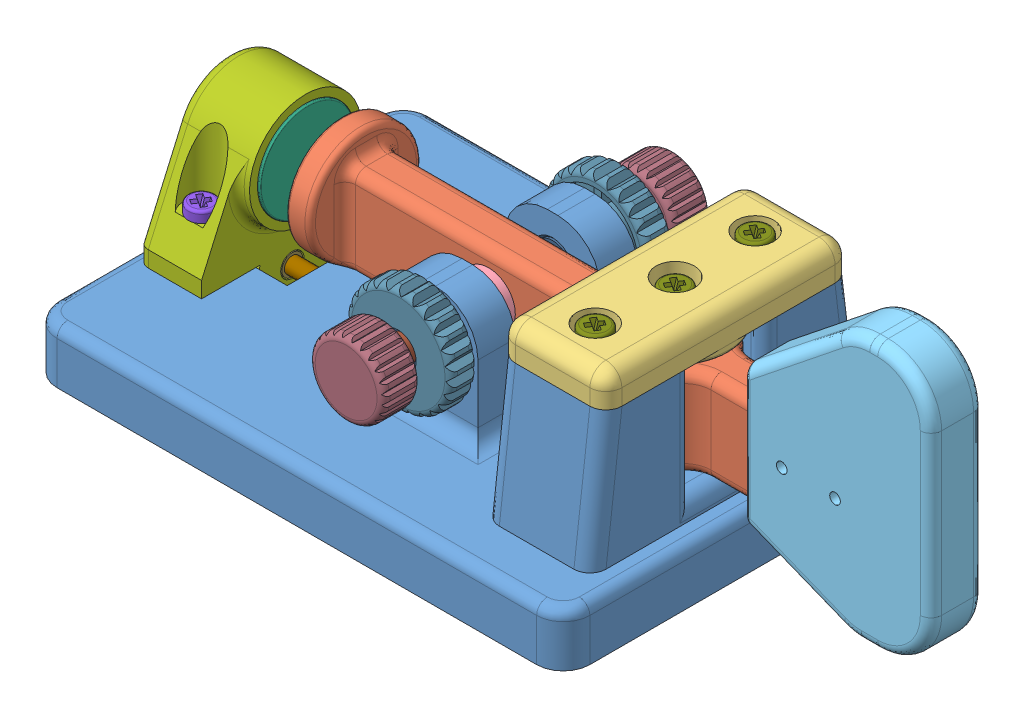
SolidWorks assembly CW Single Paddle Key Rev2, configuration Default. Lengths in mm.
Overall size (139 54 70).
37 component instances, 17 part files, 72 mates.
Components (placement in the parent):
- Base Rev2-1: Base Rev2 [Default] at (-63.1434 -3.277 40.765) size (100 35 70)
- Paddle Rev2-1: Paddle Rev2 [Default] at (-35.1434 11.723 9.765) size (102.5 21 21)
- Top plate Rev2-1: Top plate Rev2 [Default] at (12.8566 31.723 28.765) size (20 7.5 46)
- Brass Insert-1: Brass Insert [Default] at (-8.1434 20.723 -0.235) x (1 0 0) z (0 -1 0) size (10 12 10)
- Paddle Insert-1: Paddle Insert [Default] at (40.8566 26.8432 0.765) size (35 50 10)
- Magnet-1: Magnet [Default] at (-40.0834 22.223 5.765) x (0 -1 0) z (0 0 1) size (18 2.94 18)
- Magnet-2: Magnet [Default] at (-46.0834 22.223 5.765) x (0 -0.455465 0.890254) z (0 -0.890254 -0.455465) size (18 2.94 18)
- Magnet Holder- Fix for magnet-1: Magnet Holder- Fix for magnet [Default] at (-49.0234 6.723 -11.235) x (0 0 1) z (0 -1 0) size (34 14.5 33)
- M3x10 PanHd-3: M3x10 PanHd [Default] at (-54.0234 17.723 -6.235) x (-0.837169 0 -0.546944) z (-0.546944 0 0.837169) size (5 12 5)
- M3x10 PanHd-4: M3x10 PanHd [Default] at (-54.0234 17.723 17.765) x (-0.837169 0 -0.546944) z (-0.546944 0 0.837169) size (5 12 5)
- M3x20 PanHd-1: M3x20 PanHd [Default] at (-63.0234 3.7534 5.7234) x (0 -1 0) z (0 0 1) size (5 22 5)
- M5 - Brass Insert-1: M5 - Brass Insert [Default] at (-8.1434 20.723 13.765) x (1 0 0) z (0 -1 0) size (6.86 5.08 6.86)
- M5 - Brass Insert-2: M5 - Brass Insert [Default] at (-8.1434 20.723 -2.235) x (1 0 0) z (0 1 0) size (6.86 5.08 6.86)
- M5x20 PanHd-1: M5x20 PanHd [Default] at (-8.1434 20.723 34.515) x (-0.896539 0.442964 0) z (-0.442964 -0.896539 0) size (8 22.5 8)
- M5x20 PanHd-2: M5x20 PanHd [Default] at (-8.1434 20.723 -22.985) x (0.653978 -0.756513 0) z (-0.756513 -0.653978 0) size (8 22.5 8)
- M3 - Brass Insert-7: M3 - Brass Insert [Default] at (-49.0234 3.7534 5.7234) x (0 1 0) z (0 0 1) size (3.95 5.67 3.95)
- M3 - Brass Insert-8: M3 - Brass Insert [Default] at (-54.0234 6.723 -6.235) size (3.95 5.67 3.95)
- M3 - Brass Insert-9: M3 - Brass Insert [Default] at (-54.0234 6.723 17.765) size (3.95 5.67 3.95)
- Thumb End M5-1: Thumb End M5 [Default] at (-8.1434 20.723 -24.985) size (14.12 14.12 7)
- Thumb End M5-2: Thumb End M5 [Default] at (-8.1434 20.723 36.515) x (-0.923728 -0.383049 0) z (0 0 -1) size (14.12 14.12 7)
- Thumb Mid M5-1: Thumb Mid M5 [Default] at (-8.1434 20.723 -15.235) x (0.999988 0.004862 0) z (0 0 1) size (20.1 20.1 6.09)
- Thumb Mid M5-2: Thumb Mid M5 [Default] at (-8.1434 20.723 26.765) x (0.894049 0.447969 0) z (0 0 -1) size (20.1 20.1 6.09)
- M3 - Brass Insert-11: M3 - Brass Insert [Default] at (-8.1434 20.723 -10.235) x (1 0 0) z (0 1 0) size (3.95 5.67 3.95)
- M3 - Brass Insert-12: M3 - Brass Insert [Default] at (-8.1434 20.723 21.765) x (1 0 0) z (0 1 0) size (3.95 5.67 3.95)
- M3 - Brass Insert-14: M3 - Brass Insert [Default] at (22.8566 24.053 5.765) size (3.95 5.67 3.95)
- M3 - Brass Insert-15: M3 - Brass Insert [Default] at (22.8566 10.723 5.765) size (3.95 5.67 3.95)
- 3X8X4 Bearing-3: 3X8X4 Bearing [Default] at (22.8566 29.723 5.765) size (8 4 8)
- 3X8X4 Bearing-4: 3X8X4 Bearing [Default] at (22.8566 6.723 5.765) size (8 4 8)
- M3x8 PanHd-3: M3x8 PanHd [Default] at (22.8566 36.593 5.765) x (-0.837169 0 -0.546944) z (-0.546944 0 0.837169) size (5.4 10.87 5.4)
- M3x8 PanHd-4: M3x8 PanHd [Default] at (22.8566 3.853 5.765) size (5.4 10.87 5.4)
- M3x8 PanHd-5: M3x8 PanHd [Default] at (22.8566 37.593 -9.235) x (-0.837169 0 -0.546944) z (-0.546944 0 0.837169) size (5.4 10.87 5.4)
- M3x8 PanHd-6: M3x8 PanHd [Default] at (22.8566 37.593 20.765) x (-0.837169 0 -0.546944) z (-0.546944 0 0.837169) size (5.4 10.87 5.4)
- M3 - Brass Insert-16: M3 - Brass Insert [Default] at (22.8566 26.053 20.765) size (3.95 5.67 3.95)
- M3 - Brass Insert-17: M3 - Brass Insert [Default] at (22.8566 26.053 -9.235) size (3.95 5.67 3.95)
- M5 - Brass Insert-3: M5 - Brass Insert [Default] at (-8.1434 20.723 20.765) x (1 0 0) z (0 -1 0) size (6.86 5.08 6.86)
- M5 - Brass Insert-4: M5 - Brass Insert [Default] at (-8.1434 20.723 -9.235) x (1 0 0) z (0 1 0) size (6.86 5.08 6.86)
- Ring-1: Ring [Default] at (-39.6434 22.223 5.765) x (0 -1 0) z (0 0 1) size (17.7 2.5 17.7)
Mates (geometry in assembly coordinates):
- Distance1: distance = 5 mm anti-aligned: plane of Base Rev2-1 through (-63.1434 6.723 -29.235) normal (0 1 0); plane of Paddle Rev2-1 through (22.8566 11.723 5.765) normal (0 -1 0)
- Coincident1: coincident anti-aligned: plane of Base Rev2-1 through (32.8566 31.723 28.765) normal (0 1 0); plane of Top plate Rev2-1 through (12.8566 31.723 -17.235) normal (0 -1 0)
- Concentric4: concentric anti-aligned: cylinder of Paddle Rev2-1 through (-8.1434 20.723 -0.235) axis (0 0 1) radius 2; cylinder of Brass Insert-1 through (-8.1434 20.723 9.765) axis (0 0 -1) radius 1.975
- Coincident3: coincident anti-aligned: plane of Paddle Rev2-1 through (-35.1434 28.723 1.765) normal (0 0 -1); plane of Brass Insert-1 through (-8.1434 20.723 1.765) normal (0 0 1)
- Coincident4: coincident anti-aligned: plane of Paddle Rev2-1 through (22.8566 11.723 5.765) normal (0 -1 0); plane of Paddle Insert-1 through (64.8566 11.723 2.765) normal (0 1 0)
- Coincident5: coincident anti-aligned: plane of Paddle Rev2-1 through (40.8566 28.723 1.765) normal (1 0 0); plane of Paddle Insert-1 through (40.8566 34.723 10.765) normal (-1 0 0)
- Coincident6: coincident anti-aligned: plane of Paddle Rev2-1 through (62.8566 28.723 2.765) normal (0 0 -1); plane of Paddle Insert-1 through (64.8566 29.723 2.765) normal (0 0 1)
- Concentric8: concentric anti-aligned: cylinder of Paddle Rev2-1 through (-37.1434 22.223 5.765) axis (1 0 0) radius 10.5; cylinder of Magnet-1 through (-37.1434 22.223 5.765) axis (-1 0 0) radius 9
- Coincident7: coincident anti-aligned: plane of Paddle Rev2-1 through (-37.1434 22.223 5.765) normal (-1 0 0); plane of Magnet-1 through (-37.1434 22.223 5.765) normal (1 0 0)
- Concentric10: concentric anti-aligned: cylinder of Magnet-2 through (-49.0234 22.223 5.765) axis (1 0 0) radius 9; cylinder of Magnet Holder- Fix for magnet-1 through (-46.5234 22.223 5.765) axis (-1 0 0) radius 6.6
- Coincident9: coincident anti-aligned: plane of Magnet-2 through (-49.0234 22.223 5.765) normal (-1 0 0); plane of Magnet Holder- Fix for magnet-1 through (-49.0234 22.223 5.765) normal (1 0 0)
- Concentric11: concentric anti-aligned: cylinder of Magnet-1 through (-37.1434 22.223 5.765) axis (-1 0 0) radius 9; cylinder of Magnet-2 through (-49.0234 22.223 5.765) axis (1 0 0) radius 9
- Distance4: distance = 6 mm anti-aligned: plane of Magnet-2 through (-46.0834 22.223 5.765) normal (1 0 0); plane of Magnet-1 through (-40.0834 22.223 5.765) normal (-1 0 0)
- Concentric17: concentric anti-aligned: cylinder of M3x10 PanHd-4 through (-54.0234 5.723 17.765) axis (0 1 0) radius 1.5; cylinder of Magnet Holder- Fix for magnet-1 through (-54.0234 31.723 17.765) axis (0 -1 0) radius 2.2
- Coincident23: coincident anti-aligned: plane of Magnet Holder- Fix for magnet-1 through (-54.0234 15.723 17.765) normal (0 1 0); plane of M3x10 PanHd-4 through (-54.0234 15.723 17.765) normal (0 -1 0)
- Concentric18: concentric anti-aligned: cylinder of M3x10 PanHd-3 through (-54.0234 5.723 -6.235) axis (0 1 0) radius 1.5; cylinder of Magnet Holder- Fix for magnet-1 through (-54.0234 31.723 -6.235) axis (0 -1 0) radius 2.2
- Coincident24: coincident anti-aligned: plane of Magnet Holder- Fix for magnet-1 through (-54.0234 15.723 -6.235) normal (0 1 0); plane of M3x10 PanHd-3 through (-54.0234 15.723 -6.235) normal (0 -1 0)
- Concentric19: concentric aligned: cylinder of M3x20 PanHd-1 through (-41.0234 3.7534 5.7234) axis (-1 0 0) radius 1.5; cylinder of Magnet Holder- Fix for magnet-1 through (-41.0234 3.7534 5.7234) axis (-1 0 0) radius 2.2
- Coincident25: coincident anti-aligned: plane of Magnet Holder- Fix for magnet-1 through (-61.0234 22.223 5.765) normal (-1 0 0); plane of M3x20 PanHd-1 through (-61.0234 3.7534 5.7234) normal (1 0 0)
- Concentric26: concentric anti-aligned: cylinder of Base Rev2-1 through (-8.1434 20.723 -34.235) axis (0 0 1) radius 3.4; cylinder of M5 - Brass Insert-1 through (-8.1434 20.723 18.845) axis (0 0 -1) radius 3.429
- Coincident39: coincident aligned: plane of Base Rev2-1 through (-17.1434 28.723 13.765) normal (0 0 -1); plane of M5 - Brass Insert-1 through (-8.1434 20.723 13.765) normal (0 0 -1)
- Concentric27: concentric anti-aligned: cylinder of Base Rev2-1 through (-8.1434 20.723 -34.235) axis (0 0 1) radius 3.4; circle of M5 - Brass Insert-2
- Coincident40: coincident aligned: plane of Base Rev2-1 through (-17.1434 28.723 -2.235) normal (0 0 1); plane of M5 - Brass Insert-2 through (-8.1434 20.723 -2.235) normal (0 0 1)
- Concentric28: concentric anti-aligned: cylinder of M5 - Brass Insert-2 through (-8.1434 20.723 -7.315) axis (0 0 1) radius 2.5; cylinder of M5x20 PanHd-2 through (-8.1434 20.723 -0.485) axis (0 0 -1) radius 2.5
- Concentric29: concentric anti-aligned: cylinder of M5 - Brass Insert-1 through (-8.1434 20.723 18.845) axis (0 0 -1) radius 2.5; cylinder of M5x20 PanHd-1 through (-8.1434 20.723 12.015) axis (0 0 1) radius 2.5
- Distance5: distance = 0.25 mm anti-aligned: plane of M5x20 PanHd-2 through (-8.1434 20.723 -0.485) normal (0 0 1); plane of Brass Insert-1 through (-8.1434 20.723 -0.235) normal (0 0 -1)
- Distance8: distance = 0.25 mm anti-aligned: plane of M5x20 PanHd-1 through (-8.1434 20.723 12.015) normal (0 0 -1); plane of Brass Insert-1 through (-8.1434 20.723 11.765) normal (0 0 1)
- Concentric32: concentric anti-aligned: cylinder of Magnet Holder- Fix for magnet-1 through (-41.0234 3.7534 5.7234) axis (-1 0 0) radius 2.2; cylinder of M3 - Brass Insert-7 through (-54.6934 3.7534 5.7234) axis (1 0 0) radius 1.975
- Coincident45: coincident aligned: plane of Magnet Holder- Fix for magnet-1 through (-49.0234 22.223 5.765) normal (1 0 0); plane of M3 - Brass Insert-7 through (-49.0234 3.7534 5.7234) normal (1 0 0)
- Concentric34: concentric aligned: cylinder of Magnet Holder- Fix for magnet-1 through (-54.0234 31.723 17.765) axis (0 -1 0) radius 2.2; cylinder of M3 - Brass Insert-9 through (-54.0234 12.393 17.765) axis (0 -1 0) radius 1.975
- Coincident46: coincident aligned: plane of Magnet Holder- Fix for magnet-1 through (-61.0234 6.723 11.765) normal (0 -1 0); plane of M3 - Brass Insert-9 through (-54.0234 6.723 17.765) normal (0 -1 0)
- Concentric35: concentric aligned: cylinder of Magnet Holder- Fix for magnet-1 through (-54.0234 31.723 -6.235) axis (0 -1 0) radius 2.2; cylinder of M3 - Brass Insert-8 through (-54.0234 12.393 -6.235) axis (0 -1 0) radius 1.975
- Coincident47: coincident aligned: plane of Magnet Holder- Fix for magnet-1 through (-61.0234 6.723 -11.235) normal (0 -1 0); plane of M3 - Brass Insert-8 through (-54.0234 6.723 -6.235) normal (0 -1 0)
- Concentric37: concentric anti-aligned: cylinder of M5x20 PanHd-2 through (-8.1434 20.723 -20.485) axis (0 0 -1) radius 4; cylinder of Thumb End M5-1 through (-8.1434 20.723 -22.985) axis (0 0 1) radius 4.2
- Coincident49: coincident anti-aligned: plane of M5x20 PanHd-2 through (-8.1434 20.723 -22.985) normal (0 0 -1); plane of Thumb End M5-1 through (-8.1434 20.723 -22.985) normal (0 0 1)
- Concentric38: concentric anti-aligned: cylinder of Thumb End M5-2 through (-8.1434 20.723 34.515) axis (0 0 -1) radius 4.2; cylinder of M5x20 PanHd-1 through (-8.1434 20.723 32.015) axis (0 0 1) radius 4
- Coincident50: coincident anti-aligned: plane of M5x20 PanHd-1 through (-8.1434 20.723 34.515) normal (0 0 1); plane of Thumb End M5-2 through (-8.1434 20.723 34.515) normal (0 0 -1)
- Concentric39: concentric anti-aligned: cylinder of Thumb Mid M5-1 through (-8.1434 20.723 -3.835) axis (0 0 -1) radius 3.4; cylinder of M3 - Brass Insert-11 through (-8.1434 20.723 -15.905) axis (0 0 1) radius 1.975
- Coincident51: coincident aligned: plane of Thumb Mid M5-1 through (-8.1434 20.723 -10.235) normal (0 0 1); plane of M3 - Brass Insert-11 through (-8.1434 20.723 -10.235) normal (0 0 1)
- Concentric40: concentric aligned: cylinder of Thumb Mid M5-2 through (-8.1434 20.723 15.365) axis (0 0 1) radius 3.4; cylinder of M3 - Brass Insert-12 through (-8.1434 20.723 16.095) axis (0 0 1) radius 1.975
- Coincident52: coincident anti-aligned: plane of Thumb Mid M5-2 through (-8.1434 20.723 21.765) normal (0 0 -1); plane of M3 - Brass Insert-12 through (-8.1434 20.723 21.765) normal (0 0 1)
- Concentric41: concentric anti-aligned: cylinder of M5x20 PanHd-2 through (-8.1434 20.723 -0.485) axis (0 0 -1) radius 2.5; cylinder of M3 - Brass Insert-11 through (-8.1434 20.723 -15.905) axis (0 0 1) radius 1.5
- Concentric42: concentric aligned: cylinder of M5x20 PanHd-1 through (-8.1434 20.723 12.015) axis (0 0 1) radius 2.5; cylinder of M3 - Brass Insert-12 through (-8.1434 20.723 16.095) axis (0 0 1) radius 1.5
- Coincident53: coincident anti-aligned: plane of Base Rev2-1 through (-17.1434 28.723 -9.235) normal (0 0 -1); plane of Thumb Mid M5-1 through (-8.1434 20.723 -9.235) normal (0 0 1)
- Coincident54: coincident anti-aligned: plane of Base Rev2-1 through (-17.1434 28.723 20.765) normal (0 0 1); plane of Thumb Mid M5-2 through (-8.1434 20.723 20.765) normal (0 0 -1)
- Concentric52: concentric anti-aligned: cylinder of Paddle Rev2-1 through (22.8566 8.723 5.765) axis (0 1 0) radius 1.975; cylinder of M3 - Brass Insert-14 through (22.8566 29.723 5.765) axis (0 -1 0) radius 1.975
- Distance9: distance = 1 mm aligned: plane of M3 - Brass Insert-14 through (22.8566 29.723 5.765) normal (0 1 0); plane of Paddle Rev2-1 through (22.8566 28.723 5.765) normal (0 1 0)
- Concentric53: concentric anti-aligned: cylinder of Paddle Rev2-1 through (22.8566 8.723 5.765) axis (0 1 0) radius 1.975; cylinder of M3 - Brass Insert-15 through (22.8566 16.393 5.765) axis (0 -1 0) radius 1.975
- Distance10: distance = 1 mm aligned: plane of M3 - Brass Insert-15 through (22.8566 10.723 5.765) normal (0 -1 0); plane of Paddle Rev2-1 through (22.8566 11.723 5.765) normal (0 -1 0)
- Concentric54: concentric aligned: cylinder of M3 - Brass Insert-14 through (22.8566 29.723 5.765) axis (0 -1 0) radius 1.5; cylinder of 3X8X4 Bearing-3 through (22.8566 33.723 5.765) axis (0 -1 0) radius 1.5
- Coincident62: coincident anti-aligned: plane of M3 - Brass Insert-14 through (22.8566 29.723 5.765) normal (0 1 0); plane of 3X8X4 Bearing-3 through (22.8566 29.723 5.765) normal (0 -1 0)
- Concentric55: concentric anti-aligned: cylinder of M3x8 PanHd-3 through (22.8566 25.723 5.765) axis (0 1 0) radius 1.5; cylinder of 3X8X4 Bearing-3 through (22.8566 33.723 5.765) axis (0 -1 0) radius 1.5
- Coincident63: coincident anti-aligned: plane of 3X8X4 Bearing-3 through (22.8566 33.723 5.765) normal (0 1 0); plane of M3x8 PanHd-3 through (22.8566 33.723 5.765) normal (0 -1 0)
- Concentric56: concentric aligned: cylinder of M3 - Brass Insert-15 through (22.8566 16.393 5.765) axis (0 -1 0) radius 1.5; cylinder of 3X8X4 Bearing-4 through (22.8566 10.723 5.765) axis (0 -1 0) radius 1.5
- Coincident64: coincident anti-aligned: plane of M3 - Brass Insert-15 through (22.8566 10.723 5.765) normal (0 -1 0); plane of 3X8X4 Bearing-4 through (22.8566 10.723 5.765) normal (0 1 0)
- Concentric57: concentric aligned: cylinder of 3X8X4 Bearing-4 through (22.8566 10.723 5.765) axis (0 -1 0) radius 1.5; cylinder of M3x8 PanHd-4 through (22.8566 14.723 5.765) axis (0 -1 0) radius 1.5
- Coincident65: coincident anti-aligned: plane of 3X8X4 Bearing-4 through (22.8566 6.723 5.765) normal (0 -1 0); plane of M3x8 PanHd-4 through (22.8566 6.723 5.765) normal (0 1 0)
- Concentric59: concentric anti-aligned: cylinder of Base Rev2-1 through (22.8566 6.723 5.765) axis (0 1 0) radius 4.05; cylinder of 3X8X4 Bearing-4 through (22.8566 10.723 5.765) axis (0 -1 0) radius 4
- Concentric60: concentric anti-aligned: cylinder of Base Rev2-1 through (22.8566 21.723 -9.235) axis (0 1 0) radius 2.25; cylinder of M3 - Brass Insert-17 through (22.8566 31.723 -9.235) axis (0 -1 0) radius 1.975
- Concentric61: concentric anti-aligned: cylinder of Base Rev2-1 through (22.8566 21.723 20.765) axis (0 1 0) radius 2.25; cylinder of M3 - Brass Insert-16 through (22.8566 31.723 20.765) axis (0 -1 0) radius 1.975
- Coincident67: coincident aligned: plane of Base Rev2-1 through (32.8566 31.723 28.765) normal (0 1 0); plane of M3 - Brass Insert-17 through (22.8566 31.723 -9.235) normal (0 1 0)
- Coincident68: coincident aligned: plane of Base Rev2-1 through (32.8566 31.723 28.765) normal (0 1 0); plane of M3 - Brass Insert-16 through (22.8566 31.723 20.765) normal (0 1 0)
- Concentric62: concentric anti-aligned: cylinder of M3x8 PanHd-5 through (22.8566 26.723 -9.235) axis (0 1 0) radius 1.5; cylinder of M3 - Brass Insert-17 through (22.8566 31.723 -9.235) axis (0 -1 0) radius 1.5
- Concentric63: concentric anti-aligned: cylinder of M3x8 PanHd-6 through (22.8566 26.723 20.765) axis (0 1 0) radius 1.5; cylinder of M3 - Brass Insert-16 through (22.8566 31.723 20.765) axis (0 -1 0) radius 1.5
- Coincident69: coincident anti-aligned: plane of Top plate Rev2-1 through (22.8566 34.723 20.765) normal (0 1 0); plane of M3x8 PanHd-6 through (22.8566 34.723 20.765) normal (0 -1 0)
- Coincident70: coincident anti-aligned: plane of Top plate Rev2-1 through (22.8566 34.723 -9.235) normal (0 1 0); plane of M3x8 PanHd-5 through (22.8566 34.723 -9.235) normal (0 -1 0)
- Concentric64: concentric anti-aligned: cylinder of Thumb Mid M5-2 through (-8.1434 20.723 15.365) axis (0 0 1) radius 3.4; cylinder of M5 - Brass Insert-3 through (-8.1434 20.723 25.845) axis (0 0 -1) radius 3.429
- Coincident71: coincident aligned: plane of Thumb Mid M5-2 through (-8.1434 20.723 20.765) normal (0 0 -1); plane of M5 - Brass Insert-3 through (-8.1434 20.723 20.765) normal (0 0 -1)
- Concentric65: concentric anti-aligned: cylinder of Thumb Mid M5-1 through (-8.1434 20.723 -3.835) axis (0 0 -1) radius 3.4; cylinder of M5 - Brass Insert-4 through (-8.1434 20.723 -14.315) axis (0 0 1) radius 3.429
- Coincident72: coincident aligned: plane of Thumb Mid M5-1 through (-8.1434 20.723 -9.235) normal (0 0 1); plane of M5 - Brass Insert-4 through (-8.1434 20.723 -9.235) normal (0 0 1)
- Concentric66: concentric anti-aligned: cylinder of Paddle Rev2-1 through (-39.6434 22.223 5.765) axis (1 0 0) radius 9.2; cylinder of Ring-1 through (-37.1434 22.223 5.765) axis (-1 0 0) radius 8.85
- Coincident73: coincident anti-aligned: plane of Paddle Rev2-1 through (-37.1434 22.223 5.765) normal (-1 0 0); plane of Ring-1 through (-37.1434 22.223 5.765) normal (1 0 0)
